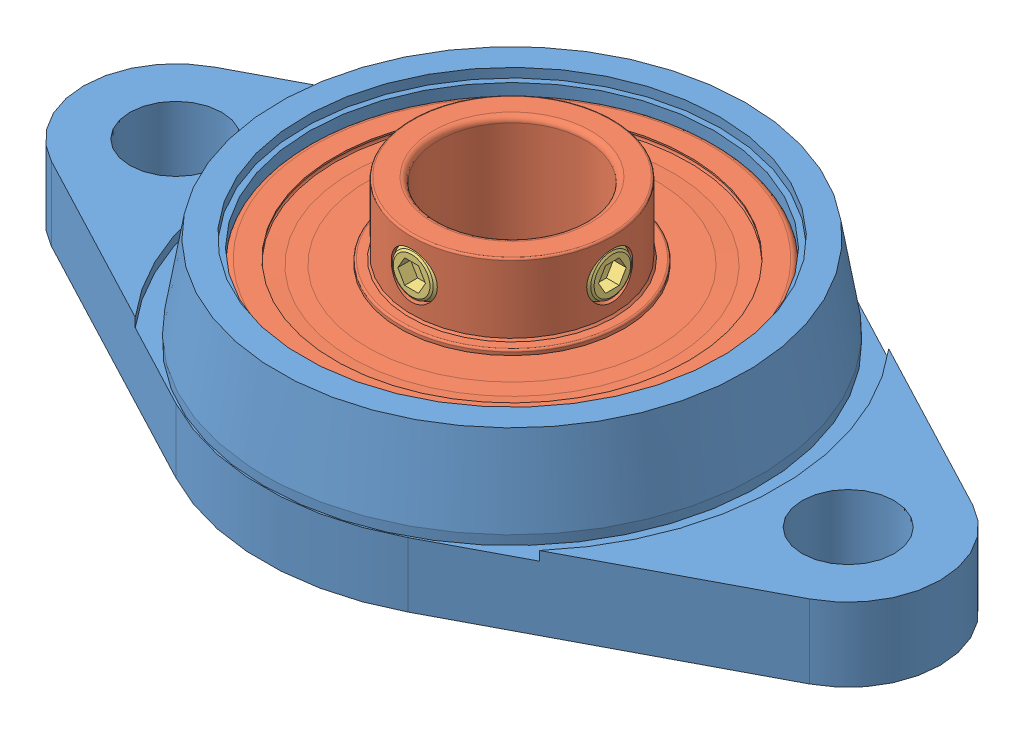
SolidWorks assembly KFL08, configuration Varsayılan. Lengths in mm.
Overall size (46.5 11.35 27).
4 component instances, 3 part files, 10 mates.
Components (placement in the parent):
- FLANGE^KFL08-1: FLANGE^KFL08 [Default] at origin size (46.5 8.5 27) (virtual)
- BEARING^KFL08-1: BEARING^KFL08 [Default] at (0 4 0) x (1 0 0) z (0 -1 0) size (22 22 10.85) (virtual)
- socket set screw cone point_am-1: socket set screw cone point_am [B18.3.6M - M2.5 x 0.45 x 2 Hex Socket Cone Pt. SS --S] at (0 9.425 5.45) x (0 0 -1) z (1 0 0) size (2 2.5 2.5)
- socket set screw cone point_am-2: socket set screw cone point_am [B18.3.6M - M2.5 x 0.45 x 2 Hex Socket Cone Pt. SS --S] at (5.45 9.425 0) x (-1 0 0) z (0 0 -1) size (2 2.5 2.5)
Mates (geometry in assembly coordinates):
- Concentric1: concentric aligned: cylinder of FLANGE^KFL08-1 through (0 4 0) axis (0 -1 0) radius 11; cylinder of BEARING^KFL08-1 through (0 0.5 0) axis (0 -1 0) radius 11
- Coincident1: coincident aligned: plane of FLANGE^KFL08-1 through (0 0.5 0) normal (0 -1 0); plane of BEARING^KFL08-1 through (0 0.5 9.6) normal (0 -1 0)
- Coincident2: coordinate: point of FLANGE^KFL08-1; point of assembly
- Coincident3: coincident aligned: plane of FLANGE^KFL08-1 through (0 0 0) normal (1 0 0); plane of BEARING^KFL08-1
- Concentric2: concentric aligned: cylinder of BEARING^KFL08-1 through (0 9.425 5.45) axis (0 0 1) radius 1.25; cylinder of socket set screw cone point_am-1 through (0 9.425 18.15) axis (0 0 1) radius 1.25
- Tangent1: tangent aligned: cylinder of BEARING^KFL08-1 through (0 0.5 0) axis (0 -1 0) radius 5.45; plane of socket set screw cone point_am-1 through (0 9.425 5.45) normal (0 0 1)
- Concentric3: concentric aligned: cylinder of BEARING^KFL08-1 through (5.45 9.425 0) axis (1 0 0) radius 1.25; cylinder of socket set screw cone point_am-2 through (18.15 9.425 0) axis (1 0 0) radius 1.25
- Tangent3: tangent aligned: cylinder of BEARING^KFL08-1 through (0 0.5 0) axis (0 -1 0) radius 5.45; plane of socket set screw cone point_am-2 through (5.45 9.425 0) normal (1 0 0)
- Parallel1: parallel aligned: plane of socket set screw cone point_am-1; plane of assembly through (0 0 0) normal (0 1 0)
- Parallel2: parallel aligned: plane of socket set screw cone point_am-2; plane of assembly through (0 0 0) normal (0 1 0)
